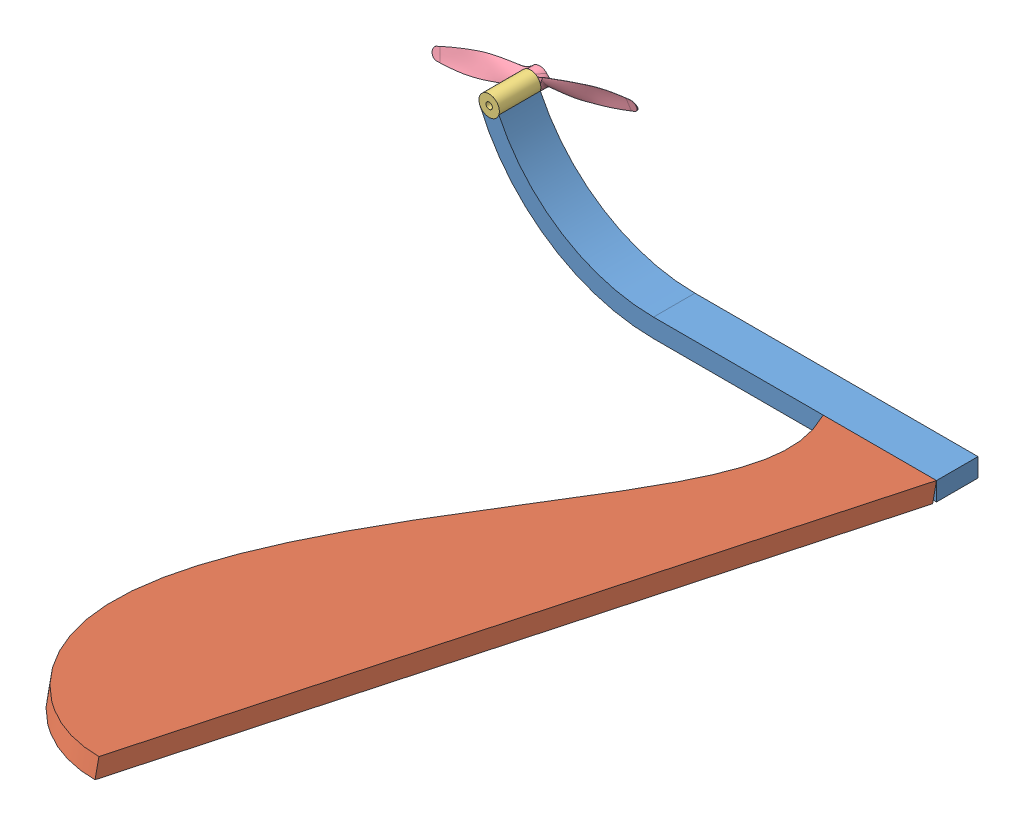
SolidWorks assembly Assem2, configuration Default. Lengths in mm.
Overall size (1021.63 703.33 253.09).
6 component instances, 4 part files, 2 mates.
Components (placement in the parent):
- bodysymfree-1: bodysymfree [Default] at (100.1378 65.2912 156.2976) x (-1 0 0) z (0 -1 0) size (110.04 212.89 47.83)
  - mp-1: mp [Default] at (9.9204 70.4329 1.4803) size (110.04 10 28.06)
  - plade 2-1: plade 2 [Default] at (-8.8992 -20.0867 -6.2821) x (0 -0.977737 -0.209833) z (0 0.209833 -0.977737) size (206.55 46.77 4.49)
- motorsym-1: motorsym [Default] at (92.5146 87.6002 85.8648) x (-0.912392 -0.409317 0) z (0.409317 -0.912392 0) size (950.73 131.02 344.34)
  - motor-1: motor [Default] at (56.1749 10 -15.5304) x (-0.204409 0 -0.978885) z (0.978885 0 -0.204409) size (4.92 13 4.92)
  - propeller-1: propeller [Default] at (54.4283 1.9853 -17.262) x (0.987389 0 -0.158315) z (0.158315 0 0.987389) size (939.94 131.02 198.03)
Mates (geometry in assembly coordinates):
- Concentric1: concentric anti-aligned: cylinder of bodysymfree-1/mp-1 through (35.7924 81.0721 75.8648) axis (0 0 1) radius 2.4614; cylinder of motorsym-1/motor-1 through (35.7924 81.0721 85.8648) axis (0 0 -1) radius 2.4614
- Coincident1: coincident aligned: plane of bodysymfree-1/mp-1 through (90.2174 63.8109 75.8648) normal (0 0 -1); plane of motorsym-1/motor-1 through (35.7924 81.0721 75.8648) normal (0 0 -1)
